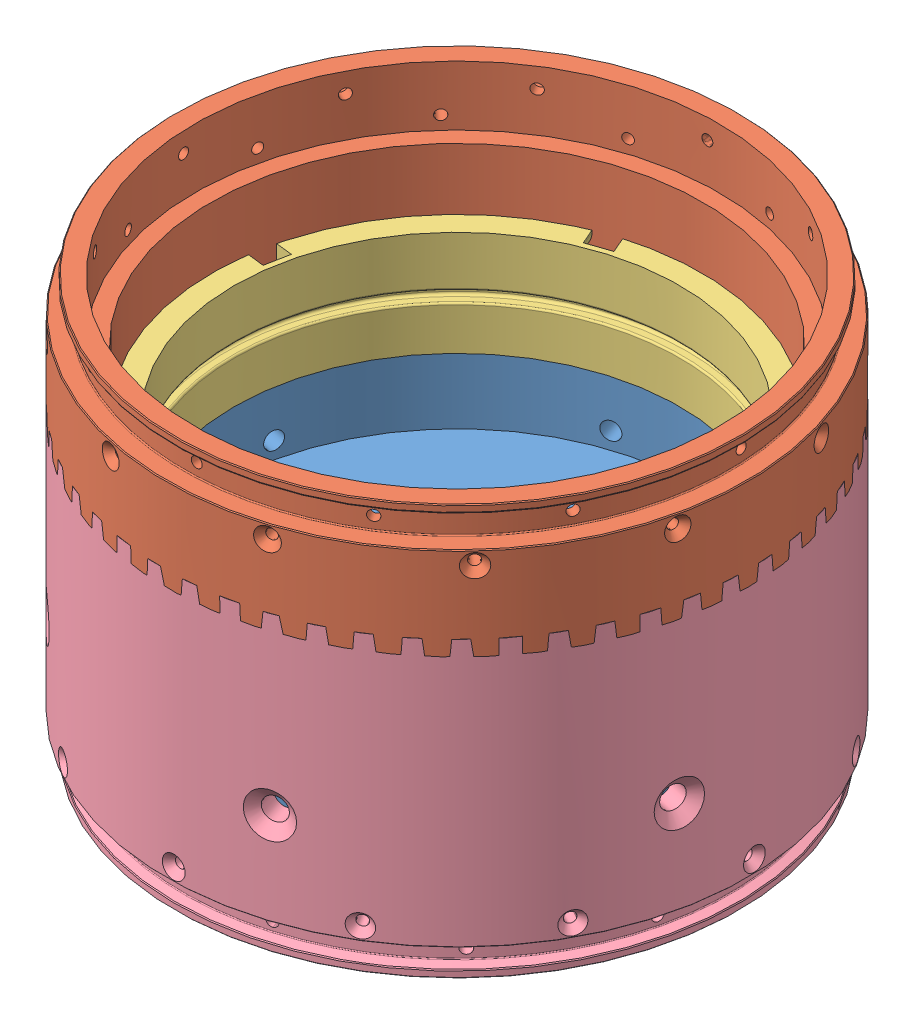
SolidWorks assembly Assy_1_V1, configuration Default. Lengths in mm.
Overall size (232.17 119.24 232.17).
4 component instances, 4 part files, 7 mates.
Components (placement in the parent):
- keeper_ring_V1-1: keeper_ring_V1 [Default] at (61.6964 61.0752 133.1263) size (151.38 34.92 151.38)
- upper_ring_V1-2: upper_ring_V1 [Default] at (61.6964 97.3668 133.1263) x (-0.935582 0 0.353111) z (-0.353111 0 -0.935582) size (168.91 49.11 168.91)
- twist_coupling_V1-1: twist_coupling_V1 [Default] at (61.6964 77.2677 133.1263) x (0.802761 0 0.5963) z (-0.5963 0 0.802761) size (151.13 30.48 151.13)
- lower_ring_V1-1: lower_ring_V1 [Default] at (61.6964 87.214 133.1263) x (0.853602 0 -0.520926) z (0.520926 0 0.853602) size (168.91 87.21 168.91)
Mates (geometry in assembly coordinates):
- Concentric1: concentric: circle of keeper_ring_V1-1; cylinder of lower_ring_V1-1 through (61.6964 87.214 133.1263) axis (0 1 0) radius 76.2
- Concentric2: concentric: cylinder of twist_coupling_V1-1 through (61.6964 138.0257 133.1263) axis (0 1 0) radius 75.565; cylinder of lower_ring_V1-1 through (61.6964 87.214 133.1263) axis (0 1 0) radius 76.2
- Concentric3: concentric: cylinder of upper_ring_V1-2 through (61.6964 146.5103 133.1263) axis (0 1 0) radius 71.4375; cylinder of lower_ring_V1-1 through (61.6964 87.214 133.1263) axis (0 1 0) radius 71.4375
- Parallel1: parallel: cylinder of upper_ring_V1-2 through (-9.0115 131.4267 199.1363) axis (0 -1 0) radius 19.05; cylinder of lower_ring_V1-1 through (116.6247 85.2734 213.2077) axis (0 1 0) radius 19.05
- Concentric4: concentric: cylinder of keeper_ring_V1-1 through (10.9039 65.9715 189.2458) axis (-0.671042 0 0.741419) radius 2.5527; cylinder of lower_ring_V1-1 through (5.0236 65.9715 195.7428) axis (-0.671042 0 0.741419) radius 3.2639
- Coincident1: coincident: plane of keeper_ring_V1-1 through (61.6964 83.3002 133.1263) normal (0 1 0); plane of twist_coupling_V1-1 through (122.3571 83.3002 178.1857) normal (0 -1 0)
- Parallel3: parallel: cylinder of upper_ring_V1-2 through (-22.9328 131.3637 86.2772) axis (0 -1 0) radius 19.05; cylinder of lower_ring_V1-1 through (2.5082 85.4338 210.1127) axis (0 1 0) radius 19.05
